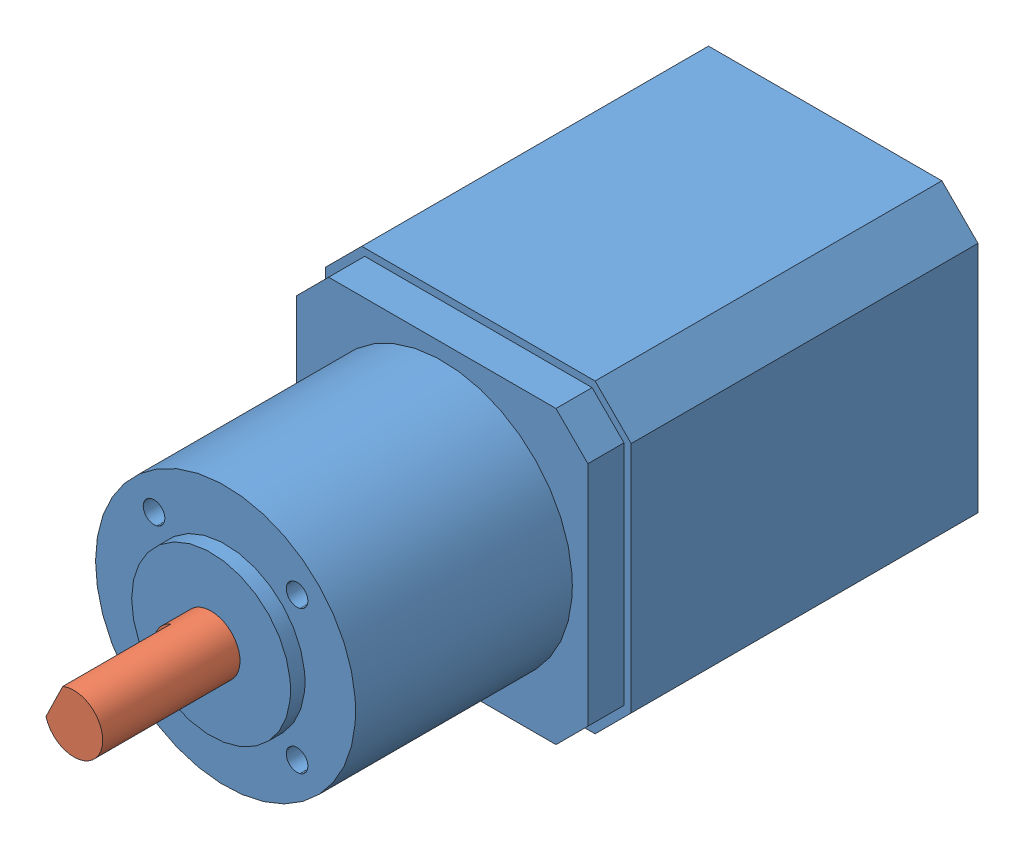
SolidWorks assembly motore_spalla, configuration Default. Lengths in mm.
Overall size (42.3 42.3 104).
2 component instances, 2 part files, 4 mates.
Components (placement in the parent):
- 17HS19-1684S-PG14-1: 17HS19-1684S-PG14 [Default] at (-7.2931 5.4422 42.5) size (42.3 42.3 85)
- albero_motore-1: albero_motore [Default] at (-7.2931 5.4422 127.5) x (0 0 1) z (-0.437031 -0.899446 0) size (19 8 8)
Mates (geometry in assembly coordinates):
- Concentrico2: concentric aligned: cylinder of 17HS19-1684S-PG14-1 through (-7.2931 5.4422 127.5) axis (0 0 -1) radius 11; cylinder of albero-1 through (-7.2931 5.4422 146.5) axis (0 0 -1) radius 4
- Coincidente1: coincident anti-aligned: plane of 17HS19-1684S-PG14-1 through (-7.2931 5.4422 127.5) normal (0 0 1); plane of albero-1 through (-7.2931 5.4422 127.5) normal (0 0 -1)
- Coincidente2: coincident anti-aligned: plane of 17HS19-1684S-PG14-1 through (-7.2931 5.4422 127.5) normal (0 0 1); plane of albero_motore-1 through (-7.2931 5.4422 127.5) normal (0 0 -1)
- Concentrico3: concentric aligned: cylinder of 17HS19-1684S-PG14-1 through (-7.2931 5.4422 127.5) axis (0 0 -1) radius 11; cylinder of albero_motore-1 through (-7.2931 5.4422 146.5) axis (0 0 -1) radius 4
